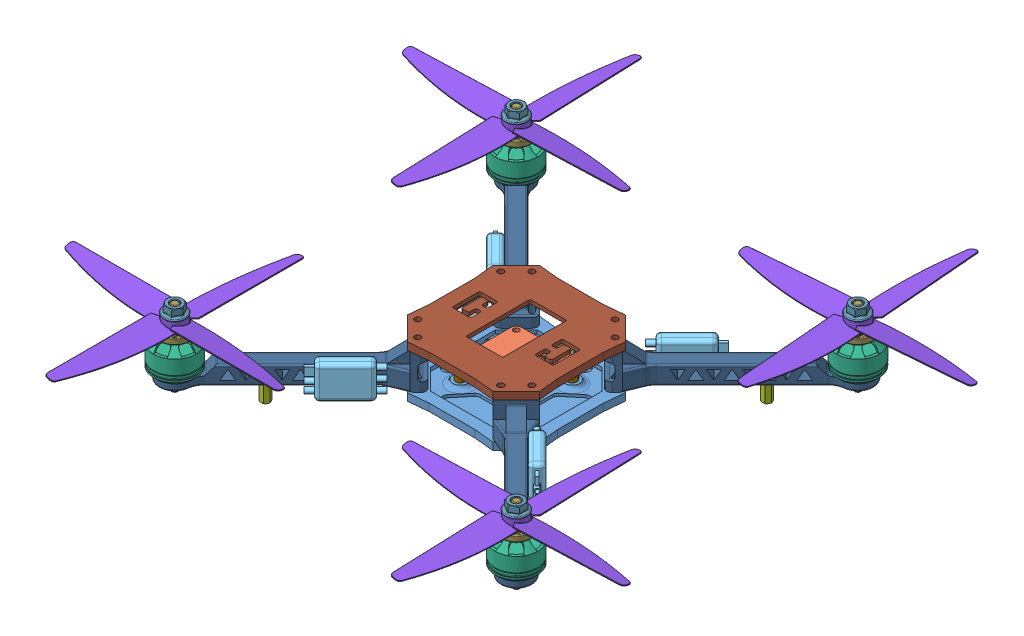
SolidWorks assembly Assem1, configuration Default. Lengths in mm.
Overall size (320.34 46.08 320.35).
69 component instances, 14 part files, 59 mates.
Components (placement in the parent):
- Spider Base-1: Spider Base [Default] at (23.733 34.9779 22.4999) size (72.13 4 72.13)
- dist Board-1: dist Board [Default] at (23.733 45.9779 57.5032) size (36 4 36)
- elecPin1-1: elecPin1 [Default] at (23.1089 44.6029 42.5032) x (0 1 0) z (-1 0 0) size (5.8 12 12.7)
- elecPin2-1: elecPin2 [Default] at (31.693 44.2479 64.2332) size (14.8 10.35 12.7)
- Electrical Connector-1: Electrical Connector [Default] at (78.4271 44.9779 95.9392) x (-0.707107 0 -0.707107) z (0 1 0) size (32 7 18)
- motor-1: motor [Default] at (117.5287 64.0579 149.8901) x (0.707107 0 -0.707107) z (0.707107 0 0.707107) size (23 22.38 23)
- piller-1: piller [Default] at (92.0681 38.9779 125.8437) x (-0.452745 0 -0.89164) z (-0.89164 0 0.452745) size (4.5 13.9 5.2)
- prop-1: prop [Default] at (116.8216 67.0579 150.5972) x (-0.999354 0 0.035936) z (-0.035936 0 -0.999354) size (127 6 127)
- Spacer-1: Spacer [Default] at (38.983 38.9779 72.7532) x (0.999834 0 -0.018246) z (0.018246 0 0.999834) size (5 6 5)
- Spider Arm-1: Spider Arm [Default] at (54.398 38.9779 74.9213) x (-0.707107 0 0.707107) z (-0.707107 0 -0.707107) size (18 20 106.15)
- Spider Top-1: Spider Top [Default] at (58.7362 62.9779 57.5032) x (0 0 -1) z (-1 0 0) size (72.13 4 72.13)
- Spinner-1: Spinner [Default] at (116.8216 60.5579 150.5972) x (0.707107 0 -0.707107) z (0.707107 0 0.707107) size (16 14.5 16)
- Spacer-2: Spacer [Default] at (38.983 38.9779 42.2532) x (0.97848 0 -0.206343) z (0.206343 0 0.97848) size (5 6 5)
- Spacer-4: Spacer [Default] at (8.483 38.9779 42.2532) x (0.910991 0 -0.412425) z (0.412425 0 0.910991) size (5 6 5)
- Spacer-6: Spacer [Default] at (8.483 38.9779 72.7532) x (0.788919 0 -0.614497) z (0.614497 0 0.788919) size (5 6 5)
- pan slot head_am-10: pan slot head_am [B18.6.7M - M2 x 0.4 x 6 Slotted PHMS --6N] at (120.3572 37.3779 154.1327) x (0 1 0) z (0 0 1) size (7.65 4 4)
- pan slot head_am-11: pan slot head_am [B18.6.7M - M2 x 0.4 x 6 Slotted PHMS --6N] at (113.2861 37.3779 154.1327) x (0 1 0) z (0 0 1) size (7.65 4 4)
- pan slot head_am-12: pan slot head_am [B18.6.7M - M2 x 0.4 x 6 Slotted PHMS --6N] at (120.3572 37.3779 147.0616) x (0 1 0) z (0 0 1) size (7.65 4 4)
- pan slot head_am-13: pan slot head_am [B18.6.7M - M2 x 0.4 x 6 Slotted PHMS --6N] at (113.2861 37.3779 147.0616) x (0 1 0) z (0 0 1) size (7.65 4 4)
- pan slot head_am-15: pan slot head_am [B18.6.7M - M2 x 0.4 x 2.5 Slotted PHMS --2.5N] at (113.6397 63.6579 153.7792) x (0 -1 0) z (0 0 1) size (4.15 4 4)
- pan slot head_am-16: pan slot head_am [B18.6.7M - M2 x 0.4 x 2.5 Slotted PHMS --2.5N] at (120.0036 63.6579 153.7792) x (0 -1 0) z (0 0 1) size (4.15 4 4)
- pan slot head_am-17: pan slot head_am [B18.6.7M - M2 x 0.4 x 2.5 Slotted PHMS --2.5N] at (113.6397 63.6579 147.4152) x (0 -1 0) z (0 0 1) size (4.15 4 4)
- pan slot head_am-19: pan slot head_am [B18.6.7M - M2 x 0.4 x 2.5 Slotted PHMS --2.5N] at (120.0036 63.6579 147.4152) x (0 -1 0) z (0 0 1) size (4.15 4 4)
- hex flange nut_am-2: hex flange nut_am [B18.2.2.4M - Hex flange nut, M5 x 0.8 --N] at (116.8216 75.0579 150.5972) x (1 0 0) z (0 1 0) size (11.8 11.8 5)
- Electrical Connector-2: Electrical Connector [Default] at (62.169 44.9779 2.809) x (-0.707107 0 0.707107) z (0 1 0) size (32 7 18)
- Electrical Connector-3: Electrical Connector [Default] at (-30.9612 44.9779 19.0672) x (0.707107 0 0.707107) z (0 1 0) size (32 7 18)
- Electrical Connector-4: Electrical Connector [Default] at (-14.7031 44.9779 112.1974) x (0.707107 0 -0.707107) z (0 1 0) size (32 7 18)
- motor-2: motor [Default] at (116.1198 64.0579 -36.2926) x (-0.707107 0 -0.707107) z (0.707107 0 -0.707107) size (23 22.38 23)
- motor-3: motor [Default] at (-70.0628 64.0579 -34.8837) x (-0.707107 0 0.707107) z (-0.707107 0 -0.707107) size (23 22.38 23)
- motor-4: motor [Default] at (-68.6539 64.0579 151.299) x (0.707107 0 0.707107) z (-0.707107 0 0.707107) size (23 22.38 23)
- piller-2: piller [Default] at (92.0734 38.9779 -10.832) x (-0.89164 0 0.452745) z (0.452745 0 0.89164) size (4.5 13.9 5.2)
- piller-3: piller [Default] at (-44.6022 38.9779 -10.8372) x (0.452745 0 0.89164) z (0.89164 0 -0.452745) size (4.5 13.9 5.2)
- piller-4: piller [Default] at (-44.6075 38.9779 125.8384) x (0.89164 0 -0.452745) z (-0.452745 0 -0.89164) size (4.5 13.9 5.2)
- Spider Arm-2: Spider Arm [Default] at (41.151 38.9779 26.8381) x (0.707107 0 0.707107) z (-0.707107 0 0.707107) size (18 20 106.15)
- Spider Arm-3: Spider Arm [Default] at (-6.9321 38.9779 40.0851) x (0.707107 0 -0.707107) z (0.707107 0 0.707107) size (18 20 106.15)
- Spider Arm-4: Spider Arm [Default] at (6.3149 38.9779 88.1683) x (-0.707107 0 -0.707107) z (0.707107 0 -0.707107) size (18 20 106.15)
- Spinner-2: Spinner [Default] at (116.8269 60.5579 -35.5855) x (-0.707107 0 -0.707107) z (0.707107 0 -0.707107) size (16 14.5 16)
- Spinner-3: Spinner [Default] at (-69.3557 60.5579 -35.5908) x (-0.707107 0 0.707107) z (-0.707107 0 -0.707107) size (16 14.5 16)
- Spinner-4: Spinner [Default] at (-69.361 60.5579 150.5919) x (0.707107 0 0.707107) z (-0.707107 0 0.707107) size (16 14.5 16)
- hex flange nut_am-3: hex flange nut_am [B18.2.2.4M - Hex flange nut, M5 x 0.8 --N] at (116.8269 75.0579 -35.5855) x (0 0 -1) z (0 1 0) size (11.8 11.8 5)
- hex flange nut_am-4: hex flange nut_am [B18.2.2.4M - Hex flange nut, M5 x 0.8 --N] at (-69.3557 75.0579 -35.5908) x (-1 0 0) z (0 1 0) size (11.8 11.8 5)
- hex flange nut_am-5: hex flange nut_am [B18.2.2.4M - Hex flange nut, M5 x 0.8 --N] at (-69.361 75.0579 150.5919) x (0 0 1) z (0 1 0) size (11.8 11.8 5)
- pan slot head_am-20: pan slot head_am [B18.6.7M - M2 x 0.4 x 2.5 Slotted PHMS --2.5N] at (113.6449 63.6579 -38.7675) x (0 -1 0) z (1 0 0) size (4.15 4 4)
- pan slot head_am-21: pan slot head_am [B18.6.7M - M2 x 0.4 x 2.5 Slotted PHMS --2.5N] at (-72.5377 63.6579 -32.4088) x (0 -1 0) z (0 0 -1) size (4.15 4 4)
- pan slot head_am-22: pan slot head_am [B18.6.7M - M2 x 0.4 x 2.5 Slotted PHMS --2.5N] at (-66.179 63.6579 153.7739) x (0 -1 0) z (-1 0 0) size (4.15 4 4)
- pan slot head_am-23: pan slot head_am [B18.6.7M - M2 x 0.4 x 2.5 Slotted PHMS --2.5N] at (113.6449 63.6579 -32.4035) x (0 -1 0) z (1 0 0) size (4.15 4 4)
- pan slot head_am-24: pan slot head_am [B18.6.7M - M2 x 0.4 x 2.5 Slotted PHMS --2.5N] at (-66.1738 63.6579 -32.4088) x (0 -1 0) z (0 0 -1) size (4.15 4 4)
- pan slot head_am-25: pan slot head_am [B18.6.7M - M2 x 0.4 x 2.5 Slotted PHMS --2.5N] at (-66.179 63.6579 147.4099) x (0 -1 0) z (-1 0 0) size (4.15 4 4)
- pan slot head_am-26: pan slot head_am [B18.6.7M - M2 x 0.4 x 2.5 Slotted PHMS --2.5N] at (120.0089 63.6579 -38.7675) x (0 -1 0) z (1 0 0) size (4.15 4 4)
- pan slot head_am-27: pan slot head_am [B18.6.7M - M2 x 0.4 x 2.5 Slotted PHMS --2.5N] at (-72.5377 63.6579 -38.7727) x (0 -1 0) z (0 0 -1) size (4.15 4 4)
- pan slot head_am-28: pan slot head_am [B18.6.7M - M2 x 0.4 x 2.5 Slotted PHMS --2.5N] at (-72.543 63.6579 153.7739) x (0 -1 0) z (-1 0 0) size (4.15 4 4)
- pan slot head_am-29: pan slot head_am [B18.6.7M - M2 x 0.4 x 2.5 Slotted PHMS --2.5N] at (120.0089 63.6579 -32.4035) x (0 -1 0) z (1 0 0) size (4.15 4 4)
- pan slot head_am-30: pan slot head_am [B18.6.7M - M2 x 0.4 x 2.5 Slotted PHMS --2.5N] at (-66.1738 63.6579 -38.7727) x (0 -1 0) z (0 0 -1) size (4.15 4 4)
- pan slot head_am-31: pan slot head_am [B18.6.7M - M2 x 0.4 x 2.5 Slotted PHMS --2.5N] at (-72.543 63.6579 147.4099) x (0 -1 0) z (-1 0 0) size (4.15 4 4)
- pan slot head_am-32: pan slot head_am [B18.6.7M - M2 x 0.4 x 6 Slotted PHMS --6N] at (113.2914 37.3779 -32.0499) x (0 1 0) z (1 0 0) size (7.65 4 4)
- pan slot head_am-33: pan slot head_am [B18.6.7M - M2 x 0.4 x 6 Slotted PHMS --6N] at (-65.8202 37.3779 -32.0552) x (0 1 0) z (0 0 -1) size (7.65 4 4)
- pan slot head_am-34: pan slot head_am [B18.6.7M - M2 x 0.4 x 6 Slotted PHMS --6N] at (-65.8255 37.3779 147.0564) x (0 1 0) z (-1 0 0) size (7.65 4 4)
- pan slot head_am-35: pan slot head_am [B18.6.7M - M2 x 0.4 x 6 Slotted PHMS --6N] at (113.2914 37.3779 -39.121) x (0 1 0) z (1 0 0) size (7.65 4 4)
- pan slot head_am-36: pan slot head_am [B18.6.7M - M2 x 0.4 x 6 Slotted PHMS --6N] at (-72.8913 37.3779 -32.0552) x (0 1 0) z (0 0 -1) size (7.65 4 4)
- pan slot head_am-37: pan slot head_am [B18.6.7M - M2 x 0.4 x 6 Slotted PHMS --6N] at (-65.8255 37.3779 154.1274) x (0 1 0) z (-1 0 0) size (7.65 4 4)
- pan slot head_am-38: pan slot head_am [B18.6.7M - M2 x 0.4 x 6 Slotted PHMS --6N] at (120.3625 37.3779 -32.0499) x (0 1 0) z (1 0 0) size (7.65 4 4)
- pan slot head_am-39: pan slot head_am [B18.6.7M - M2 x 0.4 x 6 Slotted PHMS --6N] at (-65.8202 37.3779 -39.1263) x (0 1 0) z (0 0 -1) size (7.65 4 4)
- pan slot head_am-40: pan slot head_am [B18.6.7M - M2 x 0.4 x 6 Slotted PHMS --6N] at (-72.8966 37.3779 147.0564) x (0 1 0) z (-1 0 0) size (7.65 4 4)
- pan slot head_am-41: pan slot head_am [B18.6.7M - M2 x 0.4 x 6 Slotted PHMS --6N] at (120.3625 37.3779 -39.121) x (0 1 0) z (1 0 0) size (7.65 4 4)
- pan slot head_am-42: pan slot head_am [B18.6.7M - M2 x 0.4 x 6 Slotted PHMS --6N] at (-72.8913 37.3779 -39.1263) x (0 1 0) z (0 0 -1) size (7.65 4 4)
- pan slot head_am-43: pan slot head_am [B18.6.7M - M2 x 0.4 x 6 Slotted PHMS --6N] at (-72.8966 37.3779 154.1274) x (0 1 0) z (-1 0 0) size (7.65 4 4)
- prop-2: prop [Default] at (-69.361 67.0579 150.5919) size (127 6 127)
- prop-3: prop [Default] at (-69.3557 67.0579 -35.5908) x (0.999361 0 -0.035754) z (0.035754 0 0.999361) size (127 6 127)
- prop-4: prop [Default] at (116.8269 67.0579 -35.5855) x (0.996723 0 -0.080886) z (0.080886 0 0.996723) size (127 6 127)
Mates (geometry in assembly coordinates):
- Coincident7: coincident anti-aligned: plane of Spider Base-1 through (23.733 38.9779 22.4999) normal (0 1 0); plane of Spider Arm-1 through (51.5571 38.9779 105.8387) normal (0 -1 0)
- Concentric2: concentric aligned: cylinder of Spider Base-1 through (54.843 34.9779 80.1332) axis (0 1 0) radius 1.6; cylinder of Spider Arm-1 through (54.843 38.9779 80.1332) axis (0 1 0) radius 1.5
- Parallel9: parallel anti-aligned: plane of Spider Base-1 through (47.071 38.9779 93.5692) normal (0.707107 0 0.707107); plane of Spider Arm-1 through (56.9643 50.9779 78.0119) normal (-0.707107 0 -0.707107)
- Concentric8: concentric anti-aligned: cylinder of Spider Base-1 through (38.983 34.9779 72.7532) axis (0 1 0) radius 1.5; cylinder of Spacer-1 through (38.983 44.9779 72.7532) axis (0 -1 0) radius 1.5
- Coincident9: coincident anti-aligned: plane of Spider Base-1 through (38.983 38.9779 72.7532) normal (0 1 0); plane of Spacer-1 through (38.983 38.9779 72.7532) normal (0 -1 0)
- Concentric9: concentric anti-aligned: cylinder of Spider Base-1 through (38.983 34.9779 42.2532) axis (0 1 0) radius 1.5; cylinder of Spacer-2 through (38.983 44.9779 42.2532) axis (0 -1 0) radius 1.5
- Coincident10: coincident anti-aligned: plane of Spider Base-1 through (38.983 38.9779 42.2532) normal (0 1 0); plane of Spacer-2 through (38.983 38.9779 42.2532) normal (0 -1 0)
- Concentric10: concentric anti-aligned: cylinder of Spider Base-1 through (8.483 34.9779 42.2532) axis (0 1 0) radius 1.5; cylinder of Spacer-4 through (8.483 44.9779 42.2532) axis (0 -1 0) radius 1.5
- Coincident11: coincident anti-aligned: plane of Spider Base-1 through (8.483 38.9779 42.2532) normal (0 1 0); plane of Spacer-4 through (8.483 38.9779 42.2532) normal (0 -1 0)
- Concentric11: concentric anti-aligned: cylinder of Spider Base-1 through (8.483 34.9779 72.7532) axis (0 1 0) radius 1.5; cylinder of Spacer-6 through (8.483 44.9779 72.7532) axis (0 -1 0) radius 1.5
- Coincident12: coincident anti-aligned: plane of Spider Base-1 through (8.483 38.9779 72.7532) normal (0 1 0); plane of Spacer-6 through (8.483 38.9779 72.7532) normal (0 -1 0)
- Concentric12: concentric aligned: cylinder of dist Board-1 through (8.483 46.9779 72.7532) axis (0 -1 0) radius 1.5; cylinder of Spacer-6 through (8.483 44.9779 72.7532) axis (0 -1 0) radius 1.5
- Concentric13: concentric aligned: cylinder of dist Board-1 through (38.983 46.9779 42.2532) axis (0 -1 0) radius 1.5; cylinder of Spacer-2 through (38.983 44.9779 42.2532) axis (0 -1 0) radius 1.5
- Coincident14: coincident anti-aligned: plane of dist Board-1 through (8.733 44.9779 72.5032) normal (0 -1 0); plane of Spacer-2 through (38.983 44.9779 42.2532) normal (0 1 0)
- Coincident15: coincident anti-aligned: plane of dist Board-1 through (8.733 46.9779 39.5032) normal (0 0 -1); plane of elecPin1-1 through (23.1089 44.6029 39.5032) normal (0 0 1)
- Distance3: distance = 0 mm anti-aligned: plane of elecPin1-1 through (22.8839 46.9779 30.5032) normal (0 -1 0); plane of dist Board-1 through (8.733 46.9779 72.5032) normal (0 1 0)
- Coincident18: coincident anti-aligned: plane of dist Board-1 through (8.733 46.9779 72.5032) normal (0 1 0); plane of elecPin2-1 through (41.733 46.9779 62.4632) normal (0 -1 0)
- Distance4: distance = 10 mm aligned: plane of elecPin2-1 through (41.733 47.4779 65.5032) normal (0 0 1); plane of dist Board-1 through (8.733 46.9779 75.5032) normal (0 0 1)
- Coincident20: coincident aligned: plane of elecPin2-1 through (41.733 44.2479 64.2332) normal (1 0 0); plane of dist Board-1 through (41.733 46.9779 72.5032) normal (1 0 0)
- Coincident21: coincident anti-aligned: plane of motor-1 through (117.5287 43.4779 149.8901) normal (0 -1 0); plane of Spider Arm-1 through (116.2078 43.4779 137.2555) normal (0 1 0)
- Concentric14: concentric aligned: cylinder of motor-1 through (116.8216 64.0579 150.5972) axis (0 1 0) radius 1; cylinder of Spider Arm-1 through (116.8216 38.9779 150.5972) axis (0 1 0) radius 1
- Concentric15: concentric anti-aligned: cylinder of motor-1 through (113.2861 46.9779 154.1327) axis (0 -1 0) radius 1.1; cylinder of Spider Arm-1 through (113.2861 38.9779 154.1327) axis (0 1 0) radius 1.1
- Coincident22: coincident anti-aligned: plane of motor-1 through (117.5287 60.5579 149.8901) normal (0 1 0); plane of Spinner-1 through (116.8216 60.5579 150.5972) normal (0 -1 0)
- Concentric16: concentric anti-aligned: cylinder of motor-1 through (116.8216 64.0579 150.5972) axis (0 1 0) radius 1; cylinder of Spinner-1 through (116.8216 75.0579 150.5972) axis (0 -1 0) radius 2
- Concentric17: concentric aligned: cylinder of motor-1 through (113.6397 56.5579 147.4152) axis (0 1 0) radius 1; cylinder of Spinner-1 through (113.6397 60.5579 147.4152) axis (0 1 0) radius 1.2
- Concentric24: concentric anti-aligned: cylinder of Spider Arm-1 through (120.3572 38.9779 154.1327) axis (0 1 0) radius 1.1; cylinder of pan slot head_am-10 through (120.3572 11.9779 154.1327) axis (0 -1 0) radius 2
- Coincident27: coincident anti-aligned: plane of Spider Arm-1 through (51.5571 38.9779 105.8387) normal (0 -1 0); plane of pan slot head_am-10 through (119.3572 38.9779 154.1327) normal (0 1 0)
- Concentric25: concentric anti-aligned: cylinder of Spider Arm-1 through (113.2861 38.9779 154.1327) axis (0 1 0) radius 1.1; cylinder of pan slot head_am-11 through (113.2861 11.9779 154.1327) axis (0 -1 0) radius 2
- Coincident28: coincident anti-aligned: plane of Spider Arm-1 through (51.5571 38.9779 105.8387) normal (0 -1 0); plane of pan slot head_am-11 through (112.2861 38.9779 154.1327) normal (0 1 0)
- Concentric26: concentric anti-aligned: cylinder of Spider Arm-1 through (120.3572 38.9779 147.0616) axis (0 1 0) radius 1.1; cylinder of pan slot head_am-12 through (120.3572 11.9779 147.0616) axis (0 -1 0) radius 2
- Coincident29: coincident anti-aligned: plane of Spider Arm-1 through (51.5571 38.9779 105.8387) normal (0 -1 0); plane of pan slot head_am-12 through (119.3572 38.9779 147.0616) normal (0 1 0)
- Concentric27: concentric anti-aligned: cylinder of Spider Arm-1 through (113.2861 38.9779 147.0616) axis (0 1 0) radius 1.1; cylinder of pan slot head_am-13 through (113.2861 11.9779 147.0616) axis (0 -1 0) radius 2
- Coincident30: coincident anti-aligned: plane of Spider Arm-1 through (51.5571 38.9779 105.8387) normal (0 -1 0); plane of pan slot head_am-13 through (112.2861 38.9779 147.0616) normal (0 1 0)
- Concentric351: concentric aligned: cylinder of Spinner-1 through (113.6397 60.5579 153.7792) axis (0 1 0) radius 1.2; cylinder of pan slot head_am-15 through (113.6397 89.0579 153.7792) axis (0 1 0) radius 2
- Coincident371: coincident anti-aligned: plane of Spinner-1 through (113.6397 62.0579 153.7792) normal (0 1 0); plane of pan slot head_am-15 through (114.6397 62.0579 153.7792) normal (0 -1 0)
- Concentric36: concentric aligned: cylinder of Spinner-1 through (120.0036 60.5579 153.7792) axis (0 1 0) radius 1.2; cylinder of pan slot head_am-16 through (120.0036 89.0579 153.7792) axis (0 1 0) radius 2
- Coincident38: coincident anti-aligned: plane of Spinner-1 through (120.0036 62.0579 153.7792) normal (0 1 0); plane of pan slot head_am-16 through (121.0036 62.0579 153.7792) normal (0 -1 0)
- Concentric37: concentric aligned: cylinder of Spinner-1 through (113.6397 60.5579 147.4152) axis (0 1 0) radius 1.2; cylinder of pan slot head_am-17 through (113.6397 89.0579 147.4152) axis (0 1 0) radius 2
- Coincident39: coincident anti-aligned: plane of Spinner-1 through (113.6397 62.0579 147.4152) normal (0 1 0); plane of pan slot head_am-17 through (114.6397 62.0579 147.4152) normal (0 -1 0)
- Concentric39: concentric aligned: cylinder of Spinner-1 through (120.0036 60.5579 147.4152) axis (0 1 0) radius 1.2; cylinder of pan slot head_am-19 through (120.0036 89.0579 147.4152) axis (0 1 0) radius 2
- Coincident41: coincident anti-aligned: plane of Spinner-1 through (120.0036 62.0579 147.4152) normal (0 1 0); plane of pan slot head_am-19 through (121.0036 62.0579 147.4152) normal (0 -1 0)
- Concentric48: concentric aligned: cylinder of piller-1 through (92.0681 42.8779 125.8437) axis (0 -1 0) radius 1.25; cylinder of Spider Arm-1 through (92.0681 42.9779 125.8437) axis (0 -1 0) radius 1.25
- Coincident47: coincident anti-aligned: plane of piller-1 through (92.0681 38.9779 125.8437) normal (0 1 0); plane of Spider Arm-1 through (51.5571 38.9779 105.8387) normal (0 -1 0)
- Coincident48: coincident anti-aligned: plane of Electrical Connector-1 through (73.4774 44.9779 100.889) normal (-0.707107 0 0.707107); plane of Spider Arm-1 through (111.8796 48.9779 139.2912) normal (0.707107 0 -0.707107)
- Coincident49: coincident: plane of Electrical Connector-1 through (64.9921 53.9779 92.4037) normal (-0.707107 0 -0.707107); line of Spider Arm-1 through (64.9921 47.9779 92.4037) axis (0 -1 0)
- Distance5: distance = 3 mm aligned: plane of Electrical Connector-1 through (81.9627 35.9779 109.3743) normal (0 -1 0); plane of Spider Arm-1 through (51.5571 38.9779 105.8387) normal (0 -1 0)
- Concentric49: concentric anti-aligned: cylinder of Spider Base-1 through (1.103 34.9779 26.3932) axis (0 1 0) radius 1.6; cylinder of Spider Top-1 through (1.103 62.9779 26.3932) axis (0 -1 0) radius 1.6
- Coincident51: coincident anti-aligned: plane of Spider Arm-1 through (54.1358 58.9779 79.4261) normal (0 1 0); plane of Spider Top-1 through (58.7362 58.9779 57.5032) normal (0 -1 0)
- Concentric50: concentric anti-aligned: cylinder of Spider Base-1 through (-7.377 34.9779 34.8732) axis (0 1 0) radius 1.6; cylinder of Spider Top-1 through (-7.377 62.9779 34.8732) axis (0 -1 0) radius 1.6
- Coincident52: coincident anti-aligned: plane of prop-1 through (116.8216 64.0579 150.5972) normal (0 -1 0); plane of Spinner-1 through (116.8216 64.0579 150.5972) normal (0 1 0)
- Concentric51: concentric aligned: cylinder of prop-1 through (116.8216 70.0579 150.5972) axis (0 -1 0) radius 2.5; cylinder of Spinner-1 through (116.8216 75.0579 150.5972) axis (0 -1 0) radius 2
- Coincident53: coincident anti-aligned: plane of prop-1 through (116.8216 70.0579 150.5972) normal (0 1 0); plane of hex flange nut_am-2 through (116.8216 70.0579 145.9784) normal (0 -1 0)
- Concentric52: concentric anti-aligned: cylinder of Spinner-1 through (116.8216 75.0579 150.5972) axis (0 -1 0) radius 2; cylinder of hex flange nut_am-2 through (116.8216 70.0579 150.5972) axis (0 1 0) radius 2.1
- Coincident54: coincident anti-aligned: plane of Spinner-4 through (-69.361 64.0579 150.5919) normal (0 1 0); plane of prop-2 through (-69.361 64.0579 150.5919) normal (0 -1 0)
- Concentric53: concentric aligned: cylinder of Spinner-4 through (-69.361 75.0579 150.5919) axis (0 -1 0) radius 2; cylinder of prop-2 through (-69.361 70.0579 150.5919) axis (0 -1 0) radius 2.5
- Concentric54: concentric aligned: cylinder of Spinner-2 through (116.8269 75.0579 -35.5855) axis (0 -1 0) radius 2; cylinder of prop-4 through (116.8269 70.0579 -35.5855) axis (0 -1 0) radius 2.5
- Coincident55: coincident anti-aligned: plane of Spinner-2 through (116.8269 64.0579 -35.5855) normal (0 1 0); plane of prop-4 through (116.8269 64.0579 -35.5855) normal (0 -1 0)
- Concentric55: concentric aligned: cylinder of Spinner-3 through (-69.3557 75.0579 -35.5908) axis (0 -1 0) radius 2; cylinder of prop-3 through (-69.3557 70.0579 -35.5908) axis (0 -1 0) radius 2.5
- Coincident56: coincident anti-aligned: plane of Spinner-3 through (-69.3557 64.0579 -35.5908) normal (0 1 0); plane of prop-3 through (-69.3557 64.0579 -35.5908) normal (0 -1 0)
